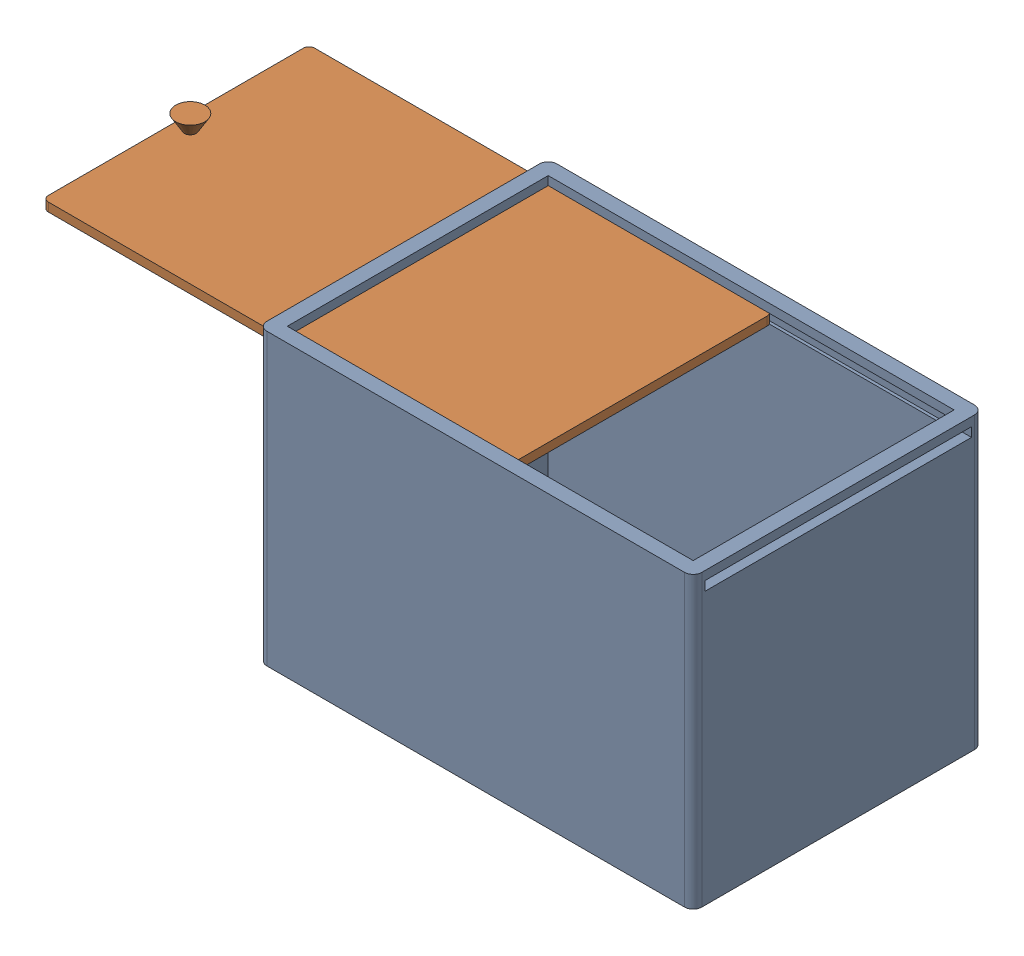
SolidWorks assembly Box_SlidingCap, configuration Default. Lengths in mm.
Overall size (228.49 101.8 100).
2 component instances, 2 part files, 4 mates.
Components (placement in the parent):
- Box-1: Box [Default] at origin size (150 100 100)
- Sliding_Cap-1: Sliding_Cap [Default] at (-73.4892 93.8 -0.05) size (160 8 91.9)
Mates (geometry in assembly coordinates):
- Parallel2: parallel aligned: plane of Box-1 through (72 100 -47) normal (0 1 0); plane of Sliding_Cap-1 through (-151.4892 96.8 -44) normal (0 1 0)
- Coincident3: coincident anti-aligned: plane of Box-1 through (-85 93.8 46) normal (0 1 0); plane of Sliding_Cap-1 through (-151.4892 93.8 -44) normal (0 -1 0)
- Coincident5: coincident anti-aligned: plane of Box-1 through (-85 97 -46) normal (0 0 1); plane of Sliding_Cap-1 through (-151.4892 96.8 -46) normal (0 0 -1)
- LimitDistance2: limit distance = 68.4892 mm aligned: plane of Sliding_Cap-1 through (6.5108 96.8 -44) normal (1 0 0); plane of Box-1 through (75 100 -47) normal (1 0 0)
